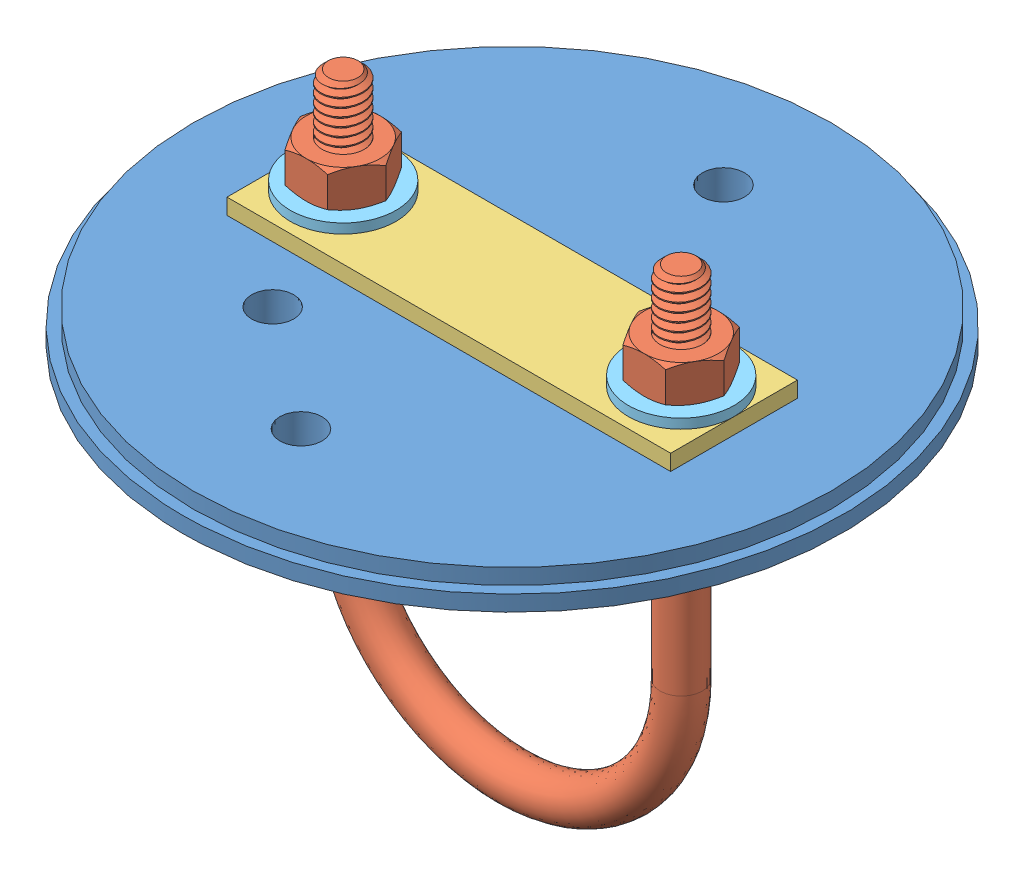
SolidWorks assembly EBayBulkheadAssembly, configuration Default. Lengths in mm.
Overall size (99.1 83.11 99.1).
10 component instances, 5 part files, 22 mates.
Components (placement in the parent):
- EBayBulkhead-1: EBayBulkhead [Default] at (31.0671 55.1815 76.8393) size (99.1 4.72 99.1)
- 3043T618_U-Bolt-1: 3043T618_U-Bolt [3043T618] at (31.0671 24.1754 76.8393) size (63.63 83.11 11.11)
- 8875T929_Mount Plate for 1 4 -20 Thread-1: 8875T929_Mount Plate for 1 4 -20 Thread [8875T929] at (31.0671 59.9015 76.8393) x (1 0 0) z (0 1 0) size (66.67 19.05 2.38)
- 91845A029_18-8 Stainless Steel Hex Nut-1: 91845A029_18-8 Stainless Steel Hex Nut [91845A029] at (5.6671 48.5743 76.8393) x (0.866025 0 0.5) z (0 -1 0) size (11.11 12.83 6.51)
- 92141A029_18-8 Stainless Steel Washer-1: 92141A029_18-8 Stainless Steel Washer [92141A029] at (5.6671 51.3525 76.8393) size (15.88 1.45 15.88)
- 92141A029_18-8 Stainless Steel Washer-2: 92141A029_18-8 Stainless Steel Washer [92141A029] at (56.4671 51.3525 76.8393) size (15.88 1.45 15.88)
- 92141A029_18-8 Stainless Steel Washer-3: 92141A029_18-8 Stainless Steel Washer [92141A029] at (56.4671 62.2828 76.8393) size (15.88 1.45 15.88)
- 92141A029_18-8 Stainless Steel Washer-4: 92141A029_18-8 Stainless Steel Washer [92141A029] at (5.6671 62.2828 76.8393) size (15.88 1.45 15.88)
- 91845A029_18-8 Stainless Steel Hex Nut-2: 91845A029_18-8 Stainless Steel Hex Nut [91845A029] at (56.4671 48.5743 76.8393) x (0.866025 0 -0.5) z (0 -1 0) size (11.11 12.83 6.51)
- 8875T929_Mount Plate for 1 4 -20 Thread-2: 8875T929_Mount Plate for 1 4 -20 Thread [8875T929] at (31.0671 55.1815 76.8393) x (1 0 0) z (0 -1 0) size (66.67 19.05 2.38)
Mates (geometry in assembly coordinates):
- Concentric1: concentric anti-aligned: cylinder of EBayBulkhead-1 through (56.4671 59.9015 76.8393) axis (0 -1 0) radius 3.175; cylinder of 3043T618_U-Bolt-1 through (56.4671 24.1754 76.8393) axis (0 1 0) radius 3.175
- Concentric2: concentric anti-aligned: cylinder of EBayBulkhead-1 through (5.6671 59.9015 76.8393) axis (0 -1 0) radius 3.175; cylinder of 3043T618_U-Bolt-1 through (5.6671 43.2254 76.8393) axis (0 1 0) radius 3.175
- Concentric3: concentric anti-aligned: cylinder of 3043T618_U-Bolt-1 through (56.4671 24.1754 76.8393) axis (0 1 0) radius 3.175; cylinder of 8875T929_Mount Plate for 1 4 -20 Thread-1 through (56.4671 62.2828 76.8393) axis (0 -1 0) radius 3.175
- Concentric4: concentric anti-aligned: cylinder of 3043T618_U-Bolt-1 through (5.6671 43.2254 76.8393) axis (0 1 0) radius 3.175; cylinder of 8875T929_Mount Plate for 1 4 -20 Thread-1 through (5.6671 62.2828 76.8393) axis (0 -1 0) radius 3.175
- Coincident1: coincident anti-aligned: cylinder of 3043T618_U-Bolt-1 through (56.4671 24.1754 76.8393) axis (0 1 0) radius 3.175; circle of 8875T929_Mount Plate for 1 4 -20 Thread-2
- Concentric5: concentric aligned: cylinder of 3043T618_U-Bolt-1 through (5.6671 43.2254 76.8393) axis (0 1 0) radius 3.175; cylinder of 8875T929_Mount Plate for 1 4 -20 Thread-2 through (5.6671 52.8003 76.8393) axis (0 1 0) radius 3.175
- Concentric6: concentric aligned: cylinder of 3043T618_U-Bolt-1 through (5.6671 43.2254 76.8393) axis (0 1 0) radius 3.175; cylinder of 92141A029_18-8 Stainless Steel Washer-1 through (5.6671 51.3525 76.8393) axis (0 1 0) radius 3.5687
- Concentric7: concentric aligned: cylinder of 3043T618_U-Bolt-1 through (5.6671 43.2254 76.8393) axis (0 1 0) radius 3.175; cylinder of 92141A029_18-8 Stainless Steel Washer-4 through (5.6671 62.2828 76.8393) axis (0 1 0) radius 3.5687
- Concentric8: concentric aligned: cylinder of 3043T618_U-Bolt-1 through (56.4671 24.1754 76.8393) axis (0 1 0) radius 3.175; cylinder of 92141A029_18-8 Stainless Steel Washer-2 through (56.4671 51.3525 76.8393) axis (0 1 0) radius 3.5687
- Concentric9: concentric aligned: cylinder of 3043T618_U-Bolt-1 through (56.4671 24.1754 76.8393) axis (0 1 0) radius 3.175; circle of 92141A029_18-8 Stainless Steel Washer-3
- Coincident2: coincident anti-aligned: cylinder of 3043T618_U-Bolt-1 through (56.4671 24.1754 76.8393) axis (0 1 0) radius 3.175; circle of 91845A029_18-8 Stainless Steel Hex Nut-2
- Coincident3: coincident anti-aligned: cylinder of 3043T618_U-Bolt-1 through (5.6671 43.2254 76.8393) axis (0 1 0) radius 3.175; circle of 91845A029_18-8 Stainless Steel Hex Nut-1
- Coincident4: coincident anti-aligned: plane of EBayBulkhead-1 through (31.0671 59.9015 76.8393) normal (0 1 0); plane of 8875T929_Mount Plate for 1 4 -20 Thread-1 through (-2.2704 59.9015 67.3143) normal (0 -1 0)
- Coincident5: coincident anti-aligned: plane of 3043T618_U-Bolt-1 through (8.8751 63.7306 82.3956) normal (0 -1 0); circle of 92141A029_18-8 Stainless Steel Washer-4
- Coincident6: coincident anti-aligned: plane of 3043T618_U-Bolt-1 through (59.6751 63.7306 82.3956) normal (0 -1 0); circle of 92141A029_18-8 Stainless Steel Washer-3
- Coincident7: coincident anti-aligned: plane of 8875T929_Mount Plate for 1 4 -20 Thread-1 through (-2.2704 62.2828 67.3143) normal (0 1 0); plane of 92141A029_18-8 Stainless Steel Washer-4 through (5.6671 62.2828 76.8393) normal (0 -1 0)
- Coincident8: coincident anti-aligned: plane of 91845A029_18-8 Stainless Steel Hex Nut-1 through (-0.7487 51.3525 76.8393) normal (0 1 0); plane of 92141A029_18-8 Stainless Steel Washer-1 through (5.6671 51.3525 76.8393) normal (0 -1 0)
- Coincident9: coincident anti-aligned: plane of 92141A029_18-8 Stainless Steel Washer-2 through (56.4671 51.3525 76.8393) normal (0 -1 0); plane of 91845A029_18-8 Stainless Steel Hex Nut-2 through (53.2592 51.3525 82.3956) normal (0 1 0)
- Coincident10: coincident anti-aligned: plane of EBayBulkhead-1 through (31.0671 55.1815 76.8393) normal (0 -1 0); plane of 8875T929_Mount Plate for 1 4 -20 Thread-2 through (-2.2704 55.1815 86.3643) normal (0 1 0)
- Coincident11: coincident anti-aligned: plane of 92141A029_18-8 Stainless Steel Washer-2 through (56.4671 52.8003 76.8393) normal (0 1 0); plane of 8875T929_Mount Plate for 1 4 -20 Thread-2 through (-2.2704 52.8003 86.3643) normal (0 -1 0)
- Coincident12: coincident anti-aligned: plane of 92141A029_18-8 Stainless Steel Washer-1 through (5.6671 52.8003 76.8393) normal (0 1 0); plane of 8875T929_Mount Plate for 1 4 -20 Thread-2 through (-2.2704 52.8003 86.3643) normal (0 -1 0)
- Coincident13: coincident aligned: plane of 91845A029_18-8 Stainless Steel Hex Nut-1 through (2.4592 45.7962 71.2831) normal (0 0 -1); plane of 91845A029_18-8 Stainless Steel Hex Nut-2 through (53.2592 45.7962 71.2831) normal (0 0 -1)
